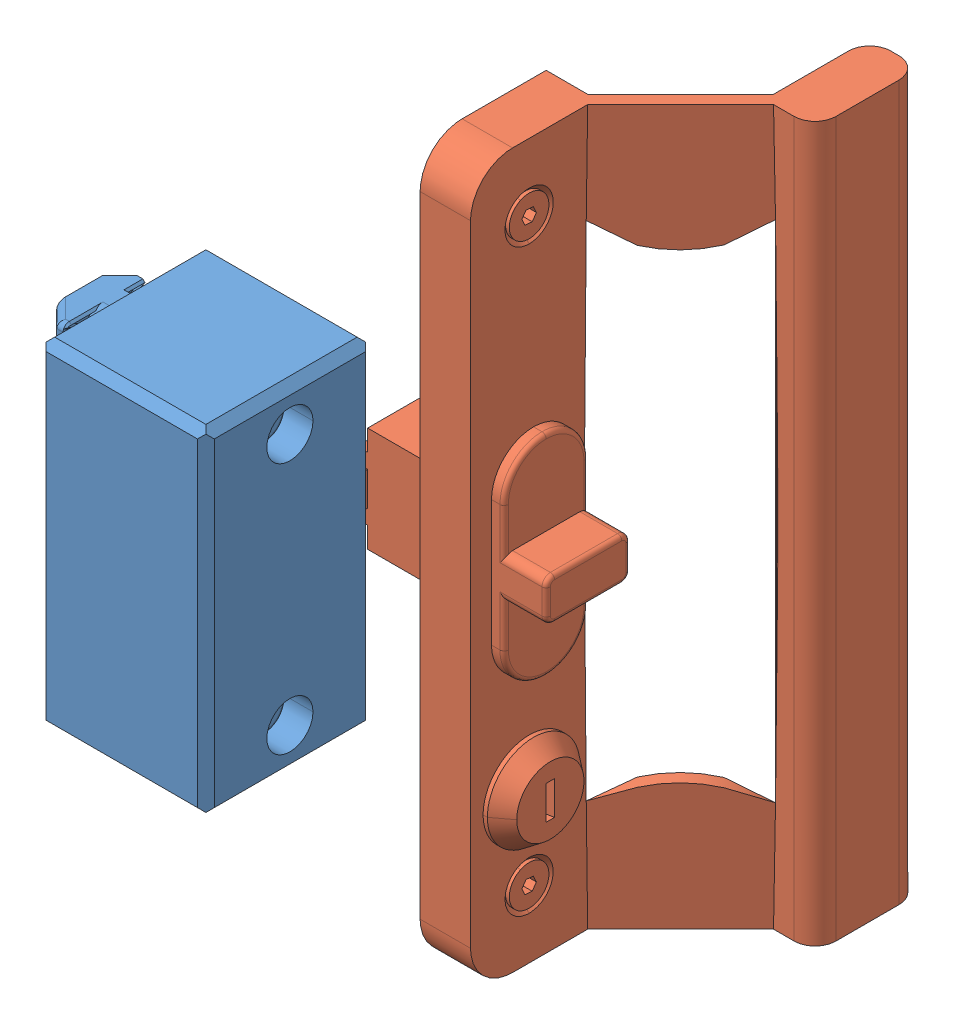
SolidWorks assembly AL-PNDS40.LK.L Замок для раздвижной двери, серия 40, левый.STEP, configuration По умолчанию. Lengths in mm.
Overall size (105.44 173.35 120.51).
2 component instances, 2 part files, 0 mates.
Components (placement in the parent):
- AL-PNDS40.LK^AL-PNDS40.LK.L Замок для раздвижной двери, серия 40, левый.STEP-1: AL-PNDS40.LK^AL-PNDS40.LK.L Замок для раздвижной двери, серия 40, левый.STEP [По умолчанию] at (-15.4271 -3.7176 0.4328) x (0 0 -1) z (1 0 0) size (40 80 52) (virtual)
- PNDS40.LK___^AL-PNDS40.LK.L Замок для раздвижной двери, серия 40, левый.STEP-1: PNDS40.LK___^AL-PNDS40.LK.L Замок для раздвижной двери, серия 40, левый.STEP [По умолчанию] at (-492.6812 -3.1345 5.7102) x (0 0 -1) z (1 0 0) size (95.51 173.35 70.45) (virtual)
